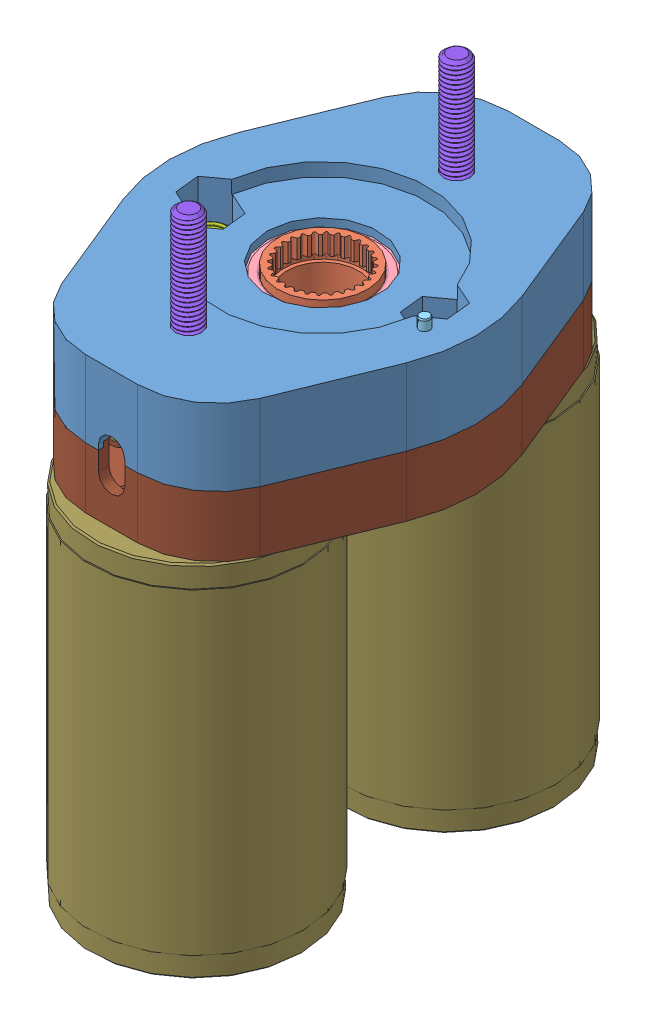
SolidWorks assembly IFI_217-3141-BAG, configuration Default. Lengths in mm.
Overall size (58 114.72 88.18).
24 component instances, 13 part files, 0 mates.
Components (placement in the parent):
- 217-3141-001 Rev1-1: 217-3141-001 Rev1 [Default] x (0 0 1) z (-1 0 0) size (80 14.5 58)
- 217-3141-007 Rev1_30T 32DP-1: 217-3141-007 Rev1_30T 32DP [Default] at (0 -7.06 0) x (0 -1 0) z (-0.999183 0 0.040426) size (22.38 25.55 25.47)
- 217-3141-006 Rev1_30T 32DP-1: 217-3141-006 Rev1_30T 32DP [Default] at (0 -9.85 -23.8887) x (-0.095925 0 -0.995389) z (0 -1 0) size (25.47 25.55 10)
- 217-3141-006 Rev1_30T 32DP-2: 217-3141-006 Rev1_30T 32DP [Default] at (0 -9.85 23.8887) x (-0.001725 0 0.999999) z (0 -1 0) size (25.47 25.55 10)
- 217-2741-1: 217-2741 [Default] at (0 2.75 0) x (0 -1 0) z (-0.999445 0 -0.033298) size (5 26 26)
- 217-2741-2: 217-2741 [Default] at (0 -13.25 0) x (0 -1 0) z (-0.537831 0 0.843053) size (5 26 26)
- PINL-M020-006-S-1: PINL-M020-006-S [Default] at (22.7445 5.75 3.4184) x (0 1 0) z (-0.890225 0 0.455522) size (6 2 2)
- SSS1032-0188-ZB-1: SSS1032-0188-ZB [Default] at (-0.3489 -11.725 -27.5094) x (-0.758755 -0.647259 0.073121) z (0.095925 0 0.995389) size (4.91 4.91 5.06)
- SSS1032-0188-ZB-2: SSS1032-0188-ZB [Default] at (-0.0063 -11.725 27.5262) x (0.762269 -0.647259 0.001315) z (0.001725 0 -0.999999) size (4.91 4.91 5.06)
- NUT-832-NYLOCK-1: NUT-832-NYLOCK [Default] at (19.244 -4.75 -2.0226) x (0.913545 0 0.406737) z (-0.406737 0 0.913545) size (10.2 4.9 8.12)
- NUT-832-NYLOCK-2: NUT-832-NYLOCK [Default] at (-19.244 -4.75 2.0226) x (0.912648 0 0.408747) z (-0.408747 0 0.912648) size (10.2 4.9 8.12)
- 91251A346_91251A346-1: 91251A346_91251A346 [Default] at (0 25.975 25.4) x (1 0 0) z (0 1 0) size (7.92 7.92 27.28)
- 91251A346_91251A346-2: 91251A346_91251A346 [Default] at (0 25.975 -25.4) x (1 0 0) z (0 1 0) size (7.92 7.92 27.28)
- SSA_SSAM4-0010ZC-1: SSA_SSAM4-0010ZC [Default] at (12.5 -17.25 -23.8887) size (7 14 7)
- SSA_SSA0832-0750ZC-1: SSA_SSA0832-0750ZC [Default] at (19.244 -19.25 -2.0226) x (-0.091926 0 -0.995766) z (-0.995766 0 0.091926) size (6.73 23.11 6.73)
- SSA_SSA0832-0750ZC-2: SSA_SSA0832-0750ZC [Default] at (-19.244 -19.25 2.0226) x (-0.18632 0 -0.982489) z (-0.982489 0 0.18632) size (6.73 23.11 6.73)
- SSA_SSAM4-0010ZC-2: SSA_SSAM4-0010ZC [Default] at (-12.5 -17.25 23.8887) x (0.677756 0 0.735287) z (-0.735287 0 0.677756) size (7 14 7)
- SSA_SSAM4-0010ZC-3: SSA_SSAM4-0010ZC [Default] at (12.5 -17.25 23.8887) x (0.994338 0 -0.106265) z (0.106265 0 0.994338) size (7 14 7)
- SSA_SSAM4-0010ZC-4: SSA_SSAM4-0010ZC [Default] at (-12.5 -17.25 -23.8887) x (0.537906 0 -0.843005) z (0.843005 0 0.537906) size (7 14 7)
- 217-3141-002 Rev2-1: 217-3141-002 Rev2 [Default] at (0 -13 0) x (0 0 1) z (0 1 0) size (80 58 12.5)
- 217-3351-1: 217-3351 [Default] at (0 -19.25 -23.8887) x (1 0 0) z (0 1 0) size (40.4 40.4 81.5)
- 217-3351-2: 217-3351 [Default] at (0 -19.25 23.8887) x (1 0 0) z (0 1 0) size (40.4 40.4 81.5)
- 217-2625-011 Rev1-1: 217-2625-011 Rev1 [Default] at (0 -11.1 -23.8887) x (0.095925 0 0.995389) z (-0.995389 0 0.095925) size (8.01 7.5 7.94)
- 217-2625-011 Rev1-2: 217-2625-011 Rev1 [Default] at (0 -11 23.8887) x (-0.964857 0 0.262777) z (-0.262777 0 -0.964857) size (8.01 7.5 7.94)
